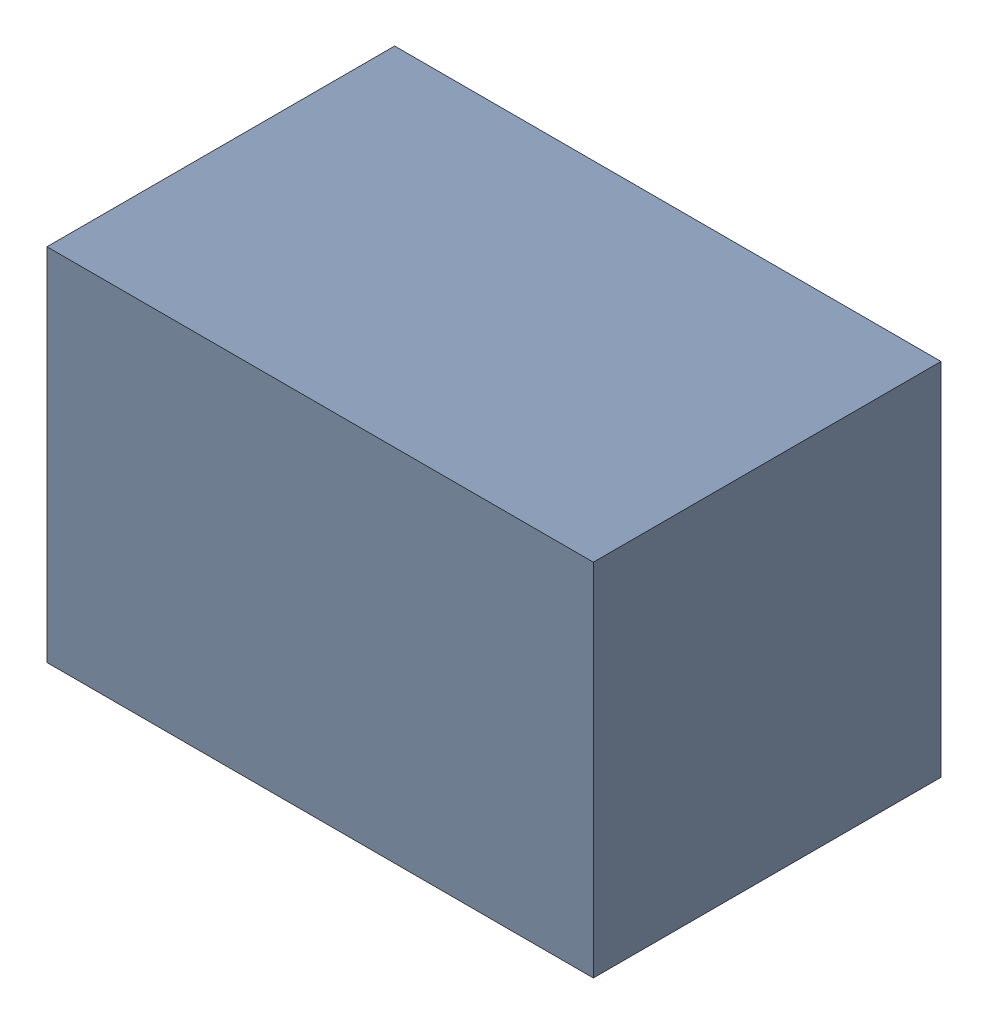
SolidWorks assembly D2-2, configuration Default. Lengths in mm.
Overall size (2.2 1.45 1.4).
2 component instances, 1 part files, 0 mates.
Components (placement in the parent):
- 959210024-2-1: 959210024-2 [Default] at (155.107 90.769 0) size (2.2 1.45 1.4)
  - Extruded-92-1: Extruded-92 [Default] at origin size (2.2 1.45 1.4)
